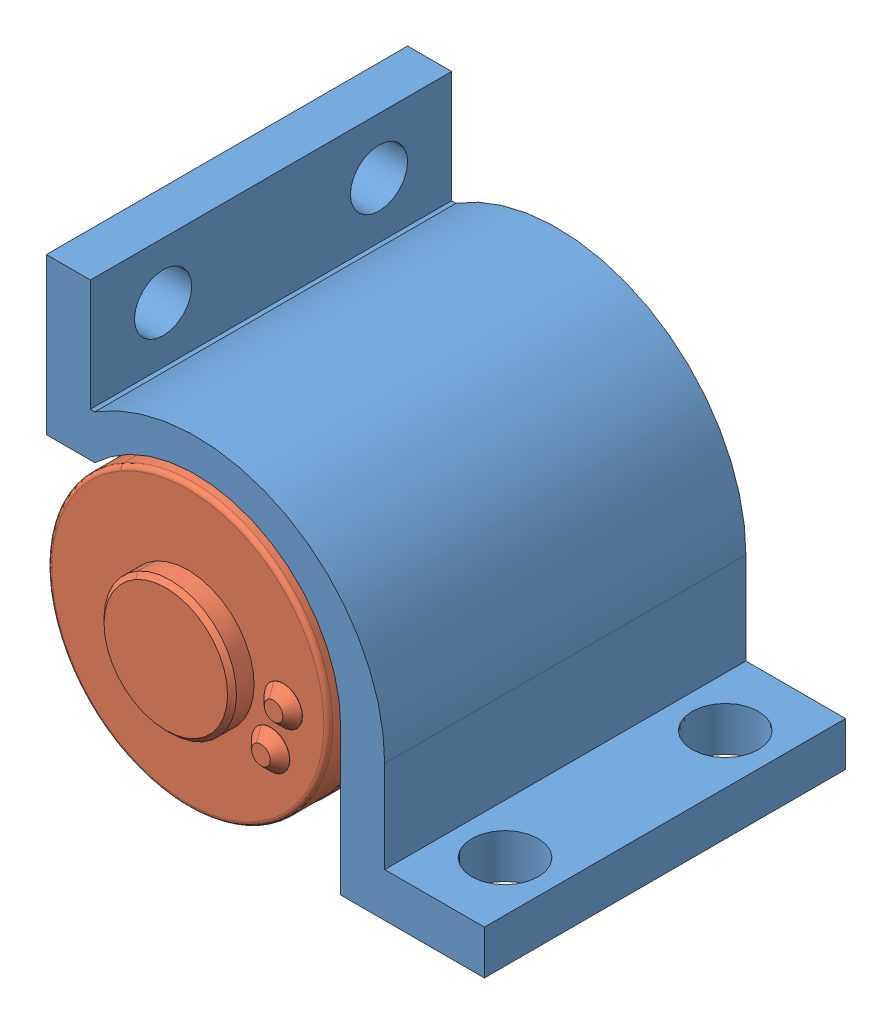
SolidWorks assembly assemblage moteur-braquette, configuration Default. Lengths in mm.
Overall size (109.16 102.81 101.22).
2 component instances, 2 part files, 1 mates.
Components (placement in the parent):
- braquette moteur-1: braquette moteur [Default] at (-5.0306 51.0768 136.1558) size (99.43 92.5 82)
- Mini CIM-v1-1: Mini CIM-v1 [Default] at (-5.0272 51.0768 52.627) x (0 0 1) z (-0.486464 0.8737 0) size (101.22 64.01 64.01)
Mates (geometry in assembly coordinates):
- Concentric1: concentric anti-aligned: circle of braquette moteur-1; circle of Mini CIM-v1-1
